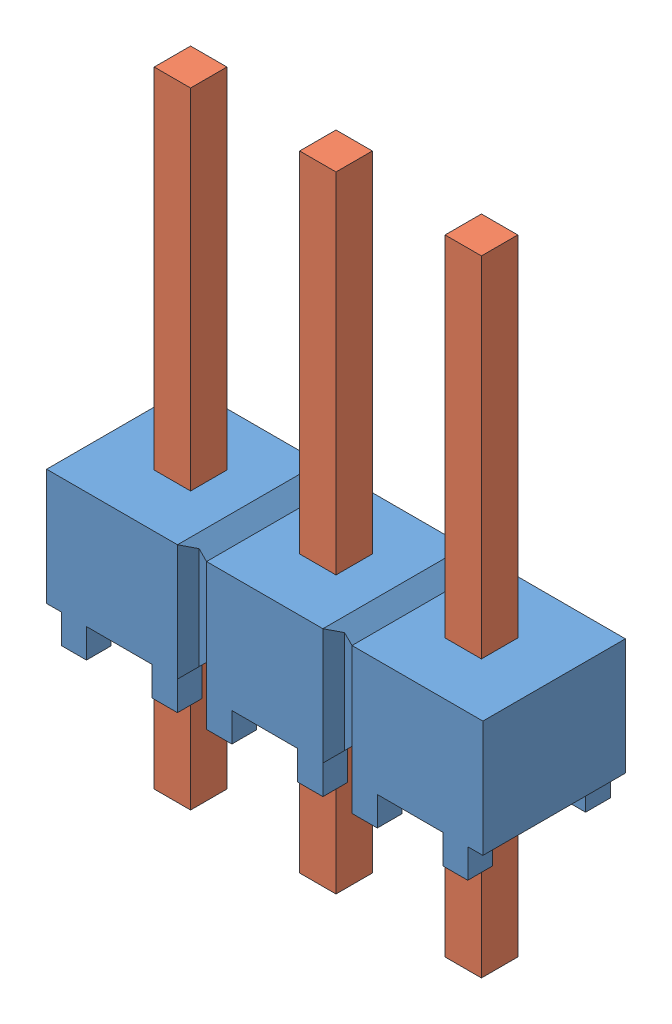
SolidWorks assembly HMTSW_103_07_G_S_240, configuration Default. Lengths in mm.
Overall size (7.62 10.92 2.49).
2 component instances, 2 part files, 0 mates.
Components (placement in the parent):
- _HMTSW_103_07_G_S_240_body_2-1: _HMTSW_103_07_G_S_240_body_2 [Default] at origin size (7.62 2.54 2.49)
- _HMTSW_103_07_S_240_4-1: _HMTSW_103_07_S_240_4 [Default] at (0 -2.286 0) size (5.97 10.92 0.89)
